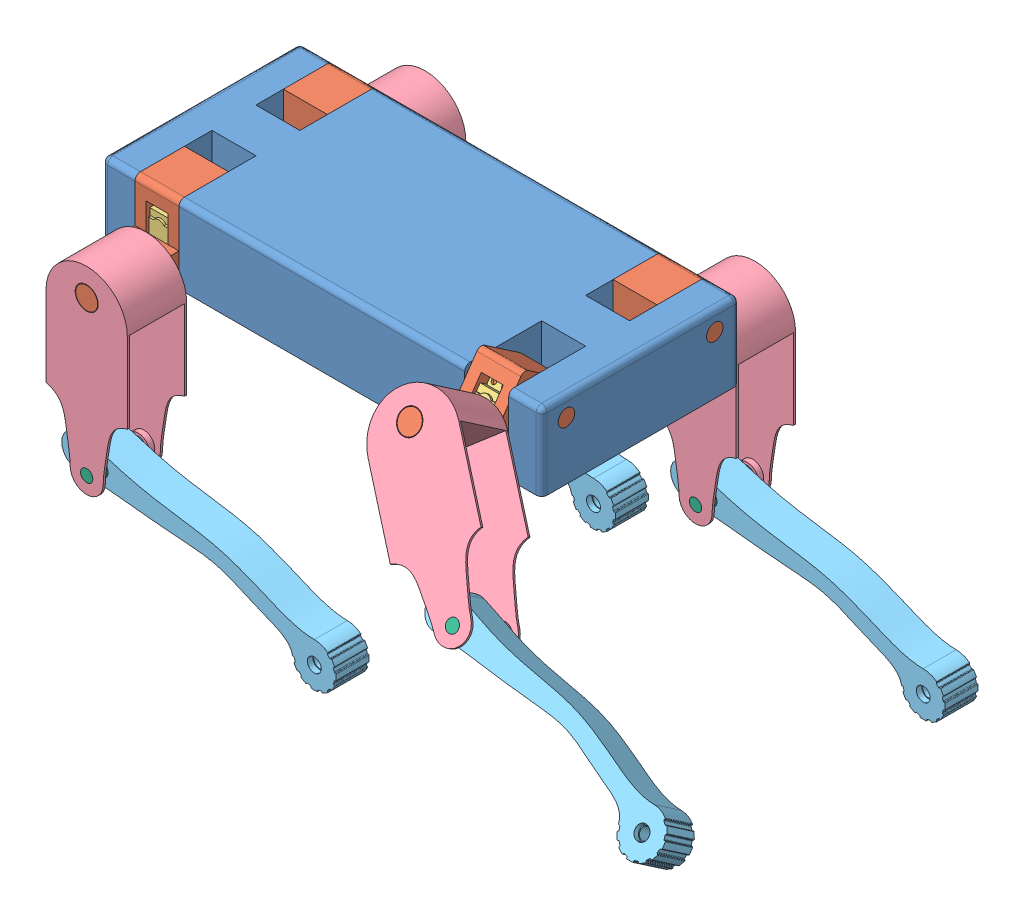
SolidWorks assembly Ensamblaje1, configuration Predeterminado. Lengths in mm.
Overall size (661.44 318.44 405.48).
21 component instances, 6 part files, 54 mates.
Components (placement in the parent):
- Pieza5-4: Pieza5 [Predeterminado] at (-178.7024 -10.8422 390) x (1 0 0) z (0 1 0) size (400 180 70)
- Pieza3-3: Pieza3 [Predeterminado] at (-148.7024 -10.8422 390) x (0 1 0) z (0 0 -1) size (70 100 109)
- PiezaM-1: PiezaM [Default] at (-128.7024 16.4078 351) x (0 1 0) z (1 0 0) size (54.5 39 20)
- Pieza3-4: Pieza3 [Predeterminado] at (151.2976 11.0739 415.7403) x (0 0.824846 -0.565357) z (0 -0.565357 -0.824846) size (70 100 109)
- PiezaM-2: PiezaM [Default] at (171.2976 11.5021 368.1653) x (0 0.824846 -0.565357) z (1 0 0) size (54.5 39 20)
- Pieza3-6: Pieza3 [Predeterminado] at (-108.7024 -10.8422 210) x (0 1 0) z (0 0 1) size (70 100 109)
- PiezaM-4: PiezaM [Default] at (-128.7024 16.4078 249) x (0 1 0) z (-1 0 0) size (54.5 39 20)
- Pieza3-7: Pieza3 [Predeterminado] at (191.2976 -10.8422 210) x (0 1 0) z (0 0 1) size (70 100 109)
- PiezaM-5: PiezaM [Default] at (171.2976 16.4078 249) x (0 1 0) z (-1 0 0) size (54.5 39 20)
- Pieza2-1: Pieza2 [Predeterminado] at (-165.7024 -150.8422 400) size (74 180 54)
- Pieza1-2: Pieza1 [Predeterminado] at (31.6105 -238.1637 442) x (-1 0 0) z (0 0 -1) size (249.88 95.94 30)
- Pieza4-1: Pieza4 [Predeterminado] at (-128.7024 -135.8422 400) size (15 15 54)
- Pieza1-8: Pieza1 [Predeterminado] at (31.6105 -238.1637 188) x (-1 0 0) z (0 0 -1) size (249.88 95.94 30)
- Pieza2-7: Pieza2 [Predeterminado] at (-165.7024 -150.8422 146) size (74 180 54)
- Pieza4-7: Pieza4 [Predeterminado] at (-128.7024 -135.8422 146) size (15 15 54)
- Pieza1-9: Pieza1 [Predeterminado] at (331.6105 -238.1637 188) x (-1 0 0) z (0 0 -1) size (249.88 95.94 30)
- Pieza2-8: Pieza2 [Predeterminado] at (134.2976 -150.8422 146) size (74 180 54)
- Pieza4-8: Pieza4 [Predeterminado] at (171.2976 -135.8422 146) size (15 15 54)
- Pieza1-10: Pieza1 [Predeterminado] at (427.8996 -115.3824 565.4567) x (-1 0 0) z (0 -0.565357 -0.824846) size (249.88 95.94 30)
- Pieza2-9: Pieza2 [Predeterminado] at (251.0444 -84.7 493.5081) x (0.72592 0.567312 -0.388841) z (0 0.565357 0.824846) size (74 180 54)
- Pieza4-9: Pieza4 [Predeterminado] at (267.5867 -54.7279 472.965) x (1 0 0) z (0 0.565357 0.824846) size (15 15 54)
Mates (geometry in assembly coordinates):
- Coincidente1: coincident anti-aligned: plane of Pieza3-3 through (-148.7024 -10.8422 351) normal (0 0 1); plane of PiezaM-1 through (-128.7024 16.4078 351) normal (0 0 -1)
- Coincidente2: coincident anti-aligned: plane of Pieza3-3 through (-148.7024 36.6578 351) normal (0 -1 0); plane of PiezaM-1 through (-118.7024 36.6578 386.5) normal (0 1 0)
- Coincidente3: coincident anti-aligned: plane of Pieza3-3 through (-118.7024 -10.8422 351) normal (-1 0 0); plane of PiezaM-1 through (-118.7024 -3.8422 386.5) normal (1 0 0)
- Coincidente4: coincident anti-aligned: plane of Pieza3-4 through (151.2976 -10.975 383.5713) normal (0 0.565357 0.824846); plane of PiezaM-2 through (171.2976 11.5021 368.1653) normal (0 -0.565357 -0.824846)
- Coincidente5: coincident anti-aligned: plane of Pieza3-4 through (151.2976 28.2052 356.7168) normal (0 -0.824846 0.565357); plane of PiezaM-2 through (181.2976 48.2754 385.9989) normal (0 0.824846 -0.565357)
- Coincidente6: coincident anti-aligned: plane of Pieza3-4 through (181.2976 -10.975 383.5713) normal (-1 0 0); plane of PiezaM-2 through (181.2976 14.8691 408.8958) normal (1 0 0)
- Concéntrica1: concentric aligned: cylinder of Pieza5-4 through (-178.7024 41.6578 367.5) axis (1 0 0) radius 7.5; cylinder of Pieza3-3 through (-178.7024 41.6578 367.5) axis (1 0 0) radius 7.5
- Coincidente7: coincident anti-aligned: plane of Pieza5-4 through (-108.7024 -10.8422 390) normal (-1 0 0); plane of Pieza3-3 through (-108.7024 -10.8422 345) normal (1 0 0)
- Coincidente11: coincident anti-aligned: plane of Pieza3-6 through (-108.7024 -10.8422 249) normal (0 0 -1); plane of PiezaM-4 through (-128.7024 16.4078 249) normal (0 0 1)
- Coincidente12: coincident anti-aligned: plane of Pieza3-6 through (-108.7024 36.6578 249) normal (0 -1 0); plane of PiezaM-4 through (-138.7024 36.6578 213.5) normal (0 1 0)
- Coincidente13: coincident anti-aligned: plane of Pieza3-6 through (-138.7024 -10.8422 249) normal (1 0 0); plane of PiezaM-4 through (-138.7024 -3.8422 213.5) normal (-1 0 0)
- Concéntrica2: concentric anti-aligned: cylinder of Pieza5-4 through (-178.7024 41.6578 367.5) axis (1 0 0) radius 7.5; cylinder of Pieza3-4 through (221.2976 41.6578 367.5) axis (-1 0 0) radius 7.5
- Coincidente14: coincident anti-aligned: plane of Pieza5-4 through (191.2976 -10.8422 390) normal (-1 0 0); plane of Pieza3-4 through (191.2976 -14.3671 378.6222) normal (1 0 0)
- Coincidente15: coincident anti-aligned: plane of Pieza3-7 through (191.2976 -10.8422 249) normal (0 0 -1); plane of PiezaM-5 through (171.2976 16.4078 249) normal (0 0 1)
- Coincidente16: coincident anti-aligned: plane of Pieza3-7 through (191.2976 36.6578 249) normal (0 -1 0); plane of PiezaM-5 through (161.2976 36.6578 213.5) normal (0 1 0)
- Coincidente17: coincident anti-aligned: plane of Pieza3-7 through (161.2976 -10.8422 249) normal (1 0 0); plane of PiezaM-5 through (161.2976 -3.8422 213.5) normal (-1 0 0)
- Concéntrica3: concentric aligned: cylinder of Pieza5-4 through (-178.7024 41.6578 232.5) axis (1 0 0) radius 7.5; cylinder of Pieza3-6 through (-178.7024 41.6578 232.5) axis (1 0 0) radius 7.5
- Coincidente18: coincident anti-aligned: plane of Pieza5-4 through (-108.7024 -10.8422 390) normal (-1 0 0); plane of Pieza3-6 through (-108.7024 59.1578 255) normal (1 0 0)
- Concéntrica4: concentric anti-aligned: cylinder of Pieza5-4 through (-178.7024 41.6578 232.5) axis (1 0 0) radius 7.5; cylinder of Pieza3-7 through (221.2976 41.6578 232.5) axis (-1 0 0) radius 7.5
- Coincidente19: coincident anti-aligned: plane of Pieza5-4 through (191.2976 -10.8422 210) normal (-1 0 0); plane of Pieza3-7 through (191.2976 59.1578 255) normal (1 0 0)
- Concéntrica5: concentric aligned: cylinder of Pieza2-1 through (-128.7024 -135.8422 474) axis (0 0 -1) radius 5.6; cylinder of Pieza4-1 through (-128.7024 -135.8422 454) axis (0 0 -1) radius 5.6
- Coincidente20: coincident aligned: plane of Pieza2-1 through (-165.7024 -150.8422 454) normal (0 0 1); plane of Pieza4-1 through (-128.7024 -135.8422 454) normal (0 0 1)
- Concéntrica6: concentric anti-aligned: cylinder of Pieza1-2 through (-128.7024 -135.8422 407) axis (0 0 1) radius 5.6; cylinder of Pieza4-1 through (-128.7024 -135.8422 454) axis (0 0 -1) radius 5.6
- Concéntrica7: concentric aligned: cylinder of Pieza2-2 through (-58.3398 -190.7995 2203.0762) axis (0 0 -1) radius 5.6; cylinder of Pieza4-2 through (-58.3398 -190.7995 2183.0762) axis (0 0 -1) radius 5.6
- Coincidente21: coincident aligned: plane of Pieza2-2 through (-95.3398 -205.7995 2183.0762) normal (0 0 1); plane of Pieza4-2 through (-58.3398 -190.7995 2183.0762) normal (0 0 1)
- Concéntrica9: concentric aligned: cylinder of Pieza2-3 through (-138.1459 -107.1634 2207.0578) axis (0 0 -1) radius 5.6; cylinder of Pieza4-3 through (-138.1459 -107.1634 2187.0578) axis (0 0 -1) radius 5.6
- Coincidente22: coincident aligned: plane of Pieza2-3 through (-175.1459 -122.1634 2187.0578) normal (0 0 1); plane of Pieza4-3 through (-138.1459 -107.1634 2187.0578) normal (0 0 1)
- Concéntrica11: concentric aligned: cylinder of Pieza2-4 through (30.4739 -67.3343 2155.0657) axis (0 0 -1) radius 5.6; cylinder of Pieza4-4 through (30.4739 -67.3343 2135.0657) axis (0 0 -1) radius 5.6
- Coincidente23: coincident aligned: plane of Pieza2-4 through (-6.5261 -82.3343 2135.0657) normal (0 0 1); plane of Pieza4-4 through (30.4739 -67.3343 2135.0657) normal (0 0 1)
- Coincidente25: coincident anti-aligned: plane of Pieza1-2 through (-37.9711 -141.7535 442) normal (0 0 1); plane of Pieza4-1 through (-128.7024 -135.8422 442) normal (0 0 -1)
- Concéntrica14: concentric aligned: cylinder of Pieza2-5 through (-296.9461 184.5051 2253.0815) axis (0 0 -1) radius 5.6; cylinder of Pieza4-5 through (-296.9461 184.5051 2233.0815) axis (0 0 -1) radius 5.6
- Coincidente26: coincident aligned: plane of Pieza2-5 through (-333.9461 169.5051 2233.0815) normal (0 0 1); plane of Pieza4-5 through (-296.9461 184.5051 2233.0815) normal (0 0 1)
- Concéntrica16: concentric aligned: cylinder of Pieza2-6 through (-296.9461 184.5051 2253.0815) axis (0 0 -1) radius 5.6; cylinder of Pieza4-6 through (-296.9461 184.5051 2233.0815) axis (0 0 -1) radius 5.6
- Coincidente28: coincident aligned: plane of Pieza2-6 through (-333.9461 169.5051 2233.0815) normal (0 0 1); plane of Pieza4-6 through (-296.9461 184.5051 2233.0815) normal (0 0 1)
- Concéntrica18: concentric aligned: cylinder of Pieza2-7 through (-128.7024 -135.8422 220) axis (0 0 -1) radius 5.6; cylinder of Pieza4-7 through (-128.7024 -135.8422 200) axis (0 0 -1) radius 5.6
- Coincidente30: coincident aligned: plane of Pieza2-7 through (-165.7024 -150.8422 200) normal (0 0 1); plane of Pieza4-7 through (-128.7024 -135.8422 200) normal (0 0 1)
- Concéntrica19: concentric anti-aligned: cylinder of Pieza1-8 through (-128.7024 -135.8422 153) axis (0 0 1) radius 5.6; cylinder of Pieza4-7 through (-128.7024 -135.8422 200) axis (0 0 -1) radius 5.6
- Coincidente31: coincident anti-aligned: plane of Pieza1-8 through (-37.9711 -141.7535 188) normal (0 0 1); plane of Pieza4-7 through (-128.7024 -135.8422 188) normal (0 0 -1)
- Concéntrica20: concentric aligned: cylinder of Pieza2-8 through (171.2976 -135.8422 220) axis (0 0 -1) radius 5.6; cylinder of Pieza4-8 through (171.2976 -135.8422 200) axis (0 0 -1) radius 5.6
- Coincidente32: coincident aligned: plane of Pieza2-8 through (134.2976 -150.8422 200) normal (0 0 1); plane of Pieza4-8 through (171.2976 -135.8422 200) normal (0 0 1)
- Concéntrica21: concentric anti-aligned: cylinder of Pieza1-9 through (171.2976 -135.8422 153) axis (0 0 1) radius 5.6; cylinder of Pieza4-8 through (171.2976 -135.8422 200) axis (0 0 -1) radius 5.6
- Coincidente33: coincident anti-aligned: plane of Pieza1-9 through (262.0289 -141.7535 188) normal (0 0 1); plane of Pieza4-8 through (171.2976 -135.8422 188) normal (0 0 -1)
- Concéntrica22: concentric aligned: cylinder of Pieza2-9 through (267.5867 -12.8915 534.0036) axis (0 -0.565357 -0.824846) radius 5.6; cylinder of Pieza4-9 through (267.5867 -24.1986 517.5067) axis (0 -0.565357 -0.824846) radius 5.6
- Coincidente34: coincident aligned: plane of Pieza2-9 through (251.0444 -54.1707 538.0498) normal (0 0.565357 0.824846); plane of Pieza4-9 through (267.5867 -24.1986 517.5067) normal (0 0.565357 0.824846)
- Concéntrica23: concentric anti-aligned: cylinder of Pieza1-10 through (267.5867 -50.7704 478.7389) axis (0 0.565357 0.824846) radius 5.6; cylinder of Pieza4-9 through (267.5867 -24.1986 517.5067) axis (0 -0.565357 -0.824846) radius 5.6
- Coincidente35: coincident anti-aligned: plane of Pieza1-10 through (358.318 -35.8588 510.9505) normal (0 0.565357 0.824846); plane of Pieza4-9 through (267.5867 -30.9829 507.6085) normal (0 -0.565357 -0.824846)
- Concéntrica24: concentric aligned: cylinder of Pieza3-3 through (-128.7024 4.1578 454) axis (0 0 -1) radius 10; cylinder of Pieza2-1 through (-128.7024 4.1578 454) axis (0 0 -1) radius 10.5
- Coincidente36: coincident anti-aligned: plane of Pieza3-3 through (-148.7024 -10.8422 400) normal (0 0 1); plane of Pieza2-1 through (-165.7024 -150.8422 400) normal (0 0 -1)
- Concéntrica25: concentric aligned: cylinder of Pieza3-4 through (171.2976 59.6295 460.0501) axis (0 -0.565357 -0.824846) radius 10; cylinder of Pieza2-9 through (171.2976 59.6295 460.0501) axis (0 -0.565357 -0.824846) radius 10.5
- Coincidente37: coincident anti-aligned: plane of Pieza3-4 through (151.2976 16.7275 423.9888) normal (0 0.565357 0.824846); plane of Pieza2-9 through (251.0444 -84.7 493.5081) normal (0 -0.565357 -0.824846)
- Concéntrica26: concentric aligned: cylinder of Pieza3-6 through (-128.7024 4.1578 146) axis (0 0 1) radius 10; circle of Pieza2-7
- Coincidente38: coincident anti-aligned: plane of Pieza3-6 through (-108.7024 -10.8422 200) normal (0 0 -1); plane of Pieza2-7 through (-165.7024 -150.8422 200) normal (0 0 1)
- Concéntrica27: concentric aligned: cylinder of Pieza3-7 through (171.2976 4.1578 146) axis (0 0 1) radius 10; circle of Pieza2-8
- Coincidente39: coincident anti-aligned: plane of Pieza3-7 through (191.2976 -10.8422 200) normal (0 0 -1); plane of Pieza2-8 through (134.2976 -150.8422 200) normal (0 0 1)
